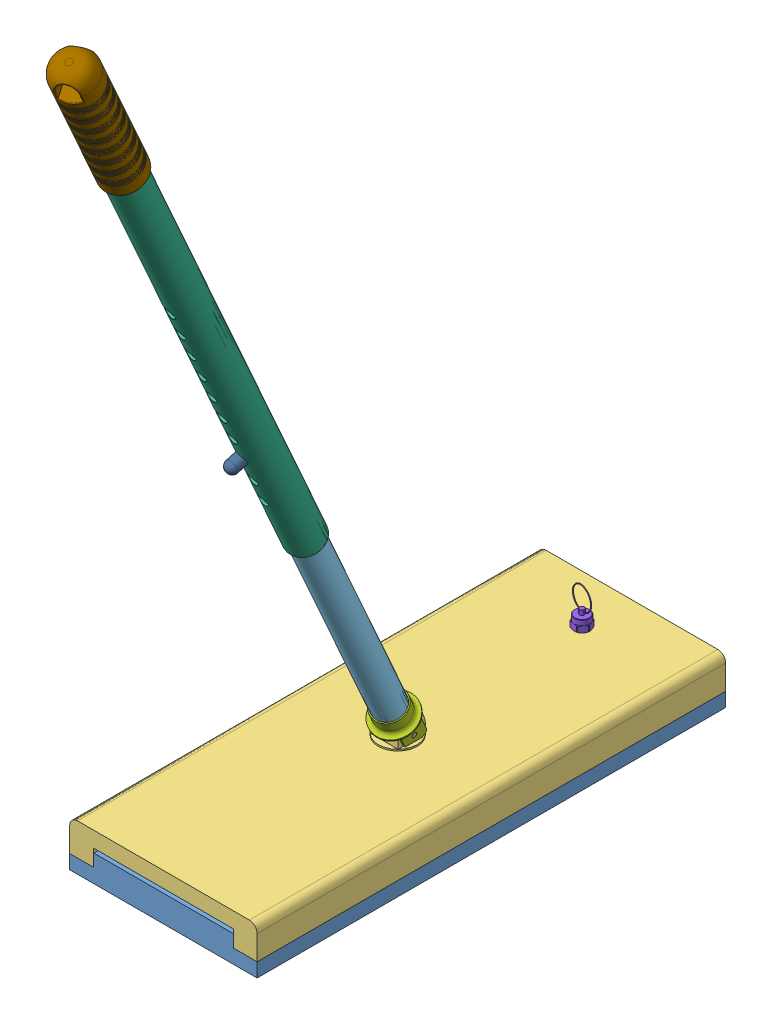
SolidWorks assembly Adjustable mop, configuration Default. Lengths in mm.
Overall size (162.29 600.58 461.26).
15 component instances, 10 part files, 14 mates.
Components (placement in the parent):
- Mop base-1: Mop base [Default] at (87.5938 97.7927 283.0682) size (120 17 300)
- Roller-1: Roller [Default] at (139.5938 103.4044 8.0682) x (1 0 0) z (0 0.986741 0.162304) size (7.6 8 8)
- Mop main body-1: Mop main body [Default] at (87.5938 99.9293 133.0682) size (120 33.64 300)
- Roller-2: Roller [Default] at (35.5938 103.4044 8.0682) x (-1 0 0) z (0 -0.986741 -0.162304) size (7.6 8 8)
- Roller-3: Roller [Default] at (139.5938 103.4044 258.0682) x (1 0 0) z (0 -0.986741 0.162304) size (7.6 8 8)
- Roller-4: Roller [Default] at (35.5938 103.4044 258.0682) x (-1 0 0) z (0 0.986741 -0.162304) size (7.6 8 8)
- coupling-1: coupling [Default] at (87.5938 131.9293 133.0686) x (0 0 -1) z (0.988457 -0.1515 0) size (17.39 9.6 21.6)
- Mop pole-1: Mop pole [Default] at (-52.7396 205.706 -410.0585) x (0.978492 -0.19116 0.077535) z (-0.156721 -0.444482 0.881972) size (28.18 790.27 132.84)
  - Mop Extender-1: Mop Extender [Default] at (193.5485 41.2467 489.8203) size (18.5 297 18.5)
  - clip-2: clip [Default] at (193.5485 480.4467 489.8203) size (8 46.52 26.67) (hidden)
  - Handle Upper Part-1: Handle Upper Part [Default] at (193.5485 386.2467 489.8203) size (22 420 22.1)
  - Coupling holder-1: Coupling holder [Default] at (193.5485 224.2467 489.8203) x (0.996158 0 -0.087573) z (0.087573 0 0.996158) size (26 24 26)
- Ring plunger-2: Ring plunger [Default] at (87.5923 142.5989 15.068) x (0.984737 0 0.174048) z (-0.174048 0 0.984737) size (14.78 39.97 10.94)
- rubber handle-1: rubber handle [Default] at (158.8569 596.7569 379.986) x (0.394168 -0.477531 0.785237) z (-0.909197 -0.077914 0.409011) size (26 105 26)
- clip-1: clip [Default] at (124.0697 370.9688 261.2956) x (0.980874 -0.174423 0.086393) z (-0.156721 -0.444482 0.881972) size (8 46.52 26.67)
Mates (geometry in assembly coordinates):
- Coincident2: coincident anti-aligned: line of Mop base-1 through (27.5938 104.2927 -16.9318) axis (0 0 1); line of Mop main body-1 through (27.5938 104.2927 283.0682) axis (0 0 -1)
- Coincident3: coincident anti-aligned: line of Mop base-1 through (147.5938 104.2927 -16.9318) axis (0 0 1); line of Mop main body-1 through (147.5938 104.2927 283.0682) axis (0 0 -1)
- Concentric1: concentric anti-aligned: cylinder of Mop base-1 through (146.5938 103.4044 8.0682) axis (-1 0 0) radius 0.5; cylinder of Roller-1 through (135.7938 103.4044 8.0682) axis (1 0 0) radius 0.5
- Coincident5: coincident aligned: circle of Base mop-1; circle of Roller-1
- Concentric2: concentric anti-aligned: cylinder of Mop main body-1 through (87.5938 131.9293 117.7636) axis (0 0 1) radius 1.5; cylinder of coupling-1 through (87.5938 131.9293 141.7636) axis (0 0 -1) radius 1.5
- Coincident6: coincident anti-aligned: circle of Base 2-1; circle of coupling-1
- Concentric3: concentric aligned: cylinder of coupling-1 through (76.9184 133.5655 133.0686) axis (0.988457 -0.1515 0) radius 1.5; cylinder of Mop pole-1/CU-1 through (74.7626 133.8959 133.0686) axis (0.988457 -0.1515 0) radius 1.5
- Coincident7: coincident aligned: circle of coupling-1; circle of Adjustable handle-1/CU-1
- Concentric5: concentric aligned: cylinder of Mop base-1 through (87.5938 109.2927 15.0682) axis (0 1 0) radius 2; cylinder of Ring plunger-2 through (87.5938 109.2927 15.0682) axis (0 1 0) radius 2
- Coincident8: coincident anti-aligned: plane of Mop base-1 through (87.5938 109.2927 15.0682) normal (0 1 0); plane of Ring plunger-2 through (86.609 109.2927 14.8941) normal (0 -1 0)
- Concentric6: concentric aligned: cylinder of Mop main body-1 through (87.5938 104.2927 15.0682) axis (0 1 0) radius 3.5; cylinder of Ring plunger-2 through (87.5938 124.5427 15.0682) axis (0 1 0) radius 3.5
- Concentric7: concentric aligned: cylinder of Mop pole-1/Handle Upper Part-1 through (178.7569 726.5933 448.9549) axis (-0.134134 -0.875154 -0.464881) radius 11; cylinder of rubber handle-1 through (158.8569 596.7569 379.986) axis (-0.134134 -0.875154 -0.464881) radius 11
- Tangent1: tangent aligned: cylinder of Mop pole-1/Extender-1 through (128.4565 398.4107 274.6247) axis (-0.134134 -0.875154 -0.464881) radius 7.65; plane of clip-1 through (119.1242 368.768 266.7013) normal (-0.156721 -0.444482 0.881972)
- Concentric9: concentric aligned: cylinder of Mop pole-1/Extender-1 through (122.3121 363.6689 266.5121) axis (0.156721 0.444482 -0.881972) radius 4; cylinder of clip-1 through (121.3091 360.8242 272.1568) axis (0.156721 0.444482 -0.881972) radius 3.9
